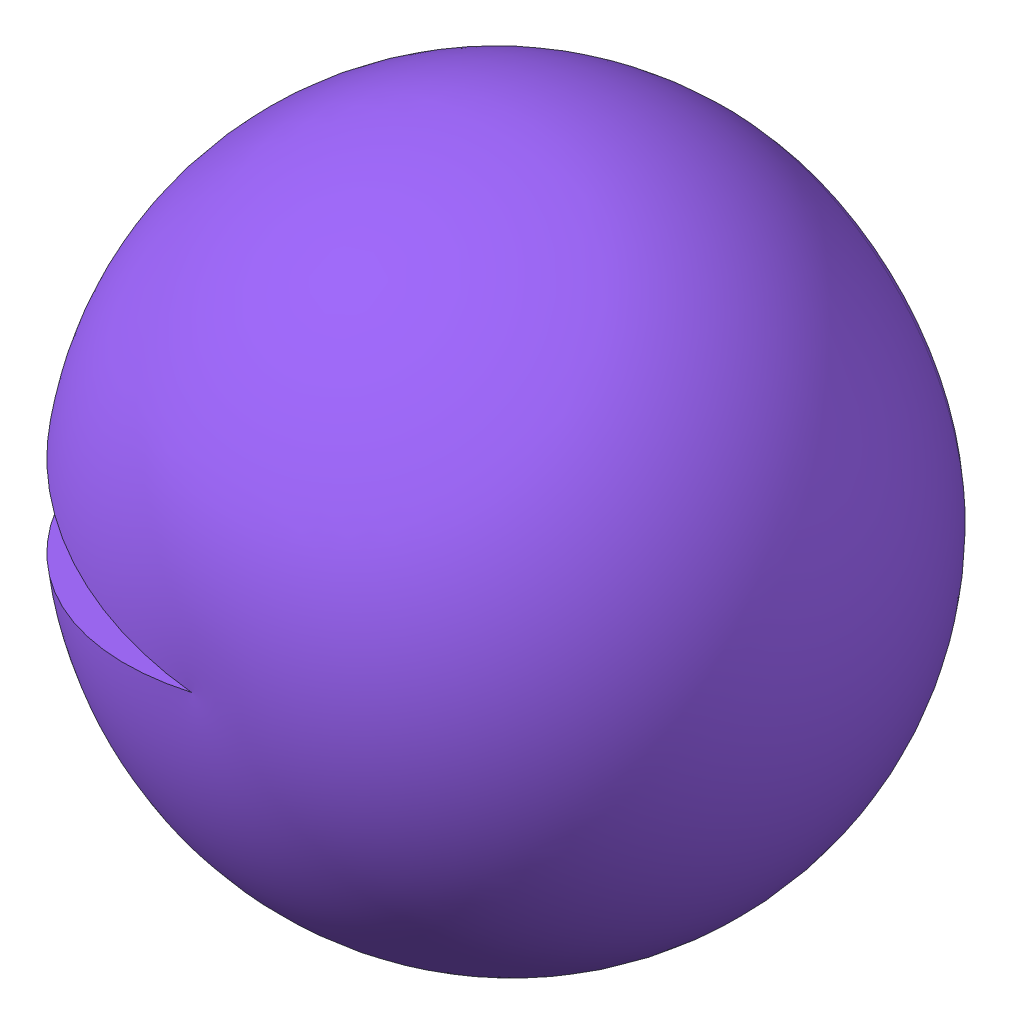
SolidWorks assembly ER7-900 机器人数模 V1.3（2016）, configuration 默认. Lengths in mm.
Overall size (1806.99 1820.82 1594.88).
8 component instances, 8 part files, 22 mates.
Components (placement in the parent):
- 底座^ER7-900 机器人数模 V1.3（2016）-1: 底座^ER7-900 机器人数模 V1.3（2016） [默认] at (-580.9049 459.3326 16.4867) x (1 0 0) z (0 -1 0) size (328.5 212 220) (virtual)
- 转座^ER7-900 机器人数模 V1.3（2016）-1: 转座^ER7-900 机器人数模 V1.3（2016） [默认] at (-556.6914 432.1392 4.9197) x (1 0 0) z (0 -1 0) size (231.5 246.5 222.89) (virtual)
- 大臂^ER7-900 机器人数模 V1.3（2016）-1: 大臂^ER7-900 机器人数模 V1.3（2016） [默认] at (-581.1049 432.3392 16.4867) x (1 0 0) z (0 -1 0) size (129.18 545 554.34) (virtual)
- 电机座^ER7-900 机器人数模 V1.3（2016）-1: 电机座^ER7-900 机器人数模 V1.3（2016） [默认] at (-581.1049 432.3392 16.4867) x (1 0 0) z (0 -1 0) size (180 160 127) (virtual)
- 手腕体^ER7-900 机器人数模 V1.3（2016）-1: 手腕体^ER7-900 机器人数模 V1.3（2016） [默认] at (-581.1049 432.3392 16.4867) x (1 0 0) z (0 -1 0) size (388.5 120.14 133.71) (virtual)
- 手腕^ER7-900 机器人数模 V1.3（2016）-1: 手腕^ER7-900 机器人数模 V1.3（2016） [默认] at (-769.9498 434.6249 1225.4207) x (0.639212 -0.000919 -0.76903) z (0 -0.999999 0.001195) size (135.71 143.05 82.25) (virtual)
- 法兰^ER7-900 机器人数模 V1.3（2016）-1: 法兰^ER7-900 机器人数模 V1.3（2016） [默认] at (556.5 0 856) x (0 -0.707107 0.707107) z (-1 0 0) size (70.2 70.2 41.7) (virtual)
- 运动范围^ER7-900 机器人数模 V1.3（2016）-1: 运动范围^ER7-900 机器人数模 V1.3（2016） [默认] x (1 0 0) z (0 -1 0) size (1806.99 1594.88 1820.82) (virtual)
Mates (geometry in assembly coordinates):
- 重合1: coordinate: point of 底座^ER7-900 机器人数模 V1.3（2016）-1; point of assembly
- 同心1: concentric anti-aligned: cylinder of 底座^ER7-900 机器人数模 V1.3（2016）-1 through (0 0 194) axis (0 0 1) radius 105; cylinder of 转座^ER7-900 机器人数模 V1.3（2016）-1 through (0 0 473.8721) axis (0 0 -1) radius 94
- 距离1: distance = 0.5 mm anti-aligned: plane of 转座^ER7-900 机器人数模 V1.3（2016）-1 through (0 0 204) normal (0 0 -1); plane of 底座^ER7-900 机器人数模 V1.3（2016）-1 through (0 0 203.5) normal (0 0 1)
- 同心2: concentric aligned: cylinder of 转座^ER7-900 机器人数模 V1.3（2016）-1 through (50 -233.6346 376) axis (0 1 0) radius 57.5; cylinder of 大臂^ER7-900 机器人数模 V1.3（2016）-1 through (50 -77.5 376) axis (0 1 0) radius 45.5
- 距离3: distance = 1 mm anti-aligned: plane of 大臂^ER7-900 机器人数模 V1.3（2016）-1 through (50 49 376) normal (0 1 0); plane of 转座^ER7-900 机器人数模 V1.3（2016）-1 through (319.8957 50 208.7799) normal (0 -1 0)
- 同心4: concentric aligned: cylinder of 大臂^ER7-900 机器人数模 V1.3（2016）-1 through (50 -49 806) axis (0 -1 0) radius 37; cylinder of 电机座^ER7-900 机器人数模 V1.3（2016）-1 through (50 46.6518 806) axis (0 -1 0) radius 37
- 距离4: distance = 1 mm anti-aligned: plane of 电机座^ER7-900 机器人数模 V1.3（2016）-1 through (50 -59 806) normal (0 -1 0); plane of 大臂^ER7-900 机器人数模 V1.3（2016）-1 through (47.0234 -60 628.4914) normal (0 1 0)
- 同心5: concentric aligned: cylinder of 电机座^ER7-900 机器人数模 V1.3（2016）-1 through (132 0 856) axis (1 0 0) radius 48; cylinder of 手腕体^ER7-900 机器人数模 V1.3（2016）-1 through (131.5 0 856) axis (1 0 0) radius 47.5
- 距离5: distance = 0.5 mm anti-aligned: plane of 电机座^ER7-900 机器人数模 V1.3（2016）-1 through (135 -2 829) normal (1 0 0); plane of 手腕体^ER7-900 机器人数模 V1.3（2016）-1 through (135.5 26 881.25) normal (-1 0 0)
- 同心6: concentric anti-aligned: cylinder of 手腕体^ER7-900 机器人数模 V1.3（2016）-1 through (477.5 -47 856) axis (0 1 0) radius 40.5; cylinder of 手腕^ER7-900 机器人数模 V1.3（2016）-1 through (477.5 -27 856) axis (0 -1 0) radius 40
- 距离6: distance = 0.5 mm anti-aligned: plane of 手腕^ER7-900 机器人数模 V1.3（2016）-1 through (477.5 -39 856) normal (0 -1 0); plane of 手腕体^ER7-900 机器人数模 V1.3（2016）-1 through (477.5 -39.5 856) normal (0 1 0)
- 同心7: concentric anti-aligned: cylinder of 手腕^ER7-900 机器人数模 V1.3（2016）-1 through (539 0 856) axis (-1 0 0) radius 37.5; cylinder of 法兰^ER7-900 机器人数模 V1.3（2016）-1 through (525 0 856) axis (1 0 0) radius 26.5
- 重合8: coincident anti-aligned: plane of 手腕^ER7-900 机器人数模 V1.3（2016）-1 through (539 0 856) normal (1 0 0); plane of 法兰^ER7-900 机器人数模 V1.3（2016）-1 through (539 0 856) normal (-1 0 0)
- LimitAngle4: limit planar angle = 0 rad aligned: plane of 底座^ER7-900 机器人数模 V1.3（2016）-1 through (-580.9049 459.3326 16.4867) normal (0 -1 0); plane of 转座^ER7-900 机器人数模 V1.3（2016）-1 through (-556.6914 432.1392 4.9197) normal (0 -1 0)
- LimitAngle5: limit planar angle = 0 rad aligned: plane of 转座^ER7-900 机器人数模 V1.3（2016）-1; plane of 大臂^ER7-900 机器人数模 V1.3（2016）-1
- LimitAngle10: limit planar angle = 0 rad aligned: plane of 电机座^ER7-900 机器人数模 V1.3（2016）-1 through (-581.1049 432.3392 16.4867) normal (0 0 1); plane of 转座^ER7-900 机器人数模 V1.3（2016）-1 through (-556.6914 432.1392 4.9197) normal (0 0 1)
- LimitAngle6: limit planar angle = 0 rad aligned: plane of 电机座^ER7-900 机器人数模 V1.3（2016）-1 through (-581.1049 432.3392 16.4867) normal (0 -1 0); plane of 手腕体^ER7-900 机器人数模 V1.3（2016）-1 through (-581.1049 432.3392 16.4867) normal (0 -1 0)
- LimitAngle8: limit planar angle = 0 rad aligned: plane of 手腕体^ER7-900 机器人数模 V1.3（2016）-1 through (-581.1049 432.3392 16.4867) normal (0 0 1); plane of 手腕^ER7-900 机器人数模 V1.3（2016）-1
- LimitAngle9: limit planar angle = 0 rad anti-aligned: plane of 法兰^ER7-900 机器人数模 V1.3（2016）-1; plane of 手腕^ER7-900 机器人数模 V1.3（2016）-1
- 重合17: coincident: point of 底座^ER7-900 机器人数模 V1.3（2016）-1; point of 运动范围^ER7-900 机器人数模 V1.3（2016）-1
- 平行5: parallel aligned: plane of 底座^ER7-900 机器人数模 V1.3（2016）-1 through (-580.9049 459.3326 16.4867) normal (0 -1 0); plane of 运动范围^ER7-900 机器人数模 V1.3（2016）-1 through (0 0 0) normal (0 -1 0)
- 重合20: coincident anti-aligned: plane of 底座^ER7-900 机器人数模 V1.3（2016）-1 through (-80 80 0) normal (0 0 -1); plane of 运动范围^ER7-900 机器人数模 V1.3（2016）-1 through (0 0 0) normal (0 0 1)
